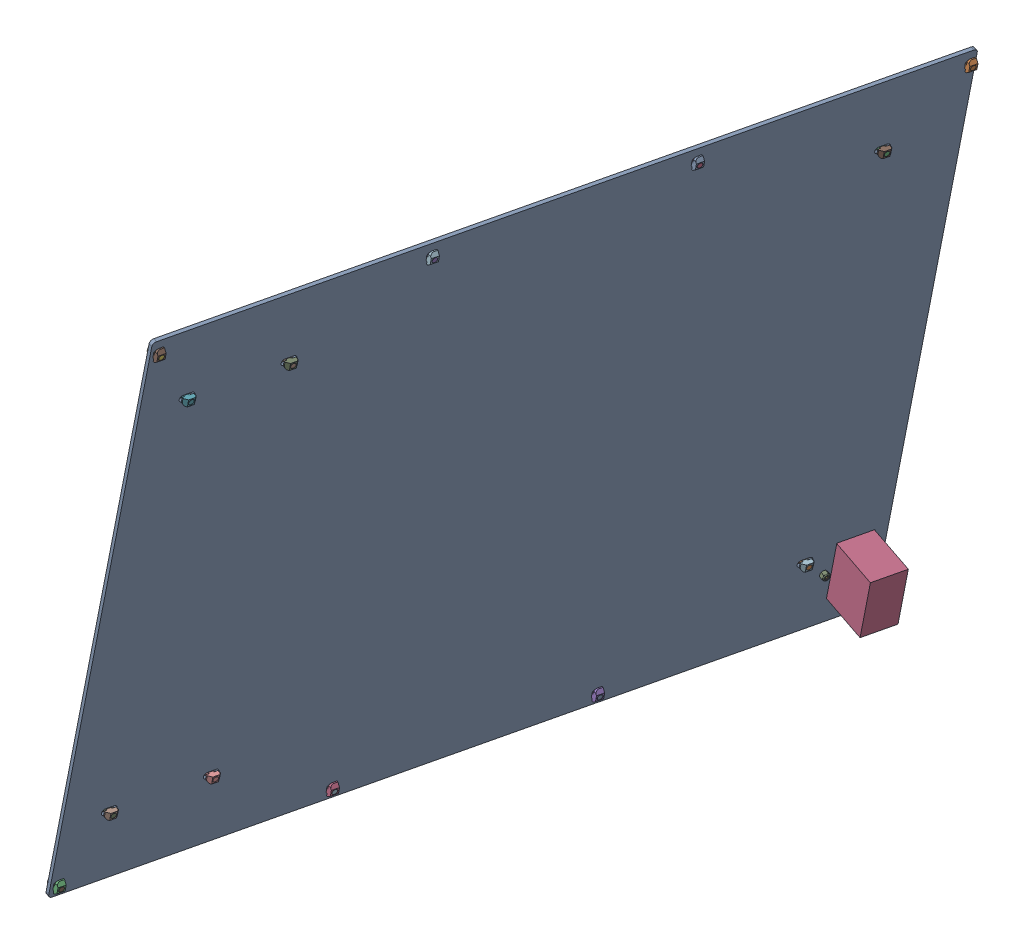
SolidWorks assembly left_side_panel_assembly, configuration Default. Lengths in mm.
Overall size (215.51 480.57 599.43).
34 component instances, 6 part files, 0 mates.
Components (placement in the parent):
- side_plates_120v side-1: side_plates_120v side [Default] at (-193.2218 26.2651 513.7471) x (0.192071 -0.031865 -0.980864) z (0.961323 -0.194929 0.194577) size (604 470 3)
- m5_low_profile_screw_template_M5 x 8-1: m5_low_profile_screw_template_M5 x 8 [Default] at (20.3229 456.5561 -69.1022) x (0.961323 -0.194929 0.194577) z (-0.194022 0.022125 0.980748) size (9.62 9 9)
- m5_low_profile_screw_template_M5 x 8-2: m5_low_profile_screw_template_M5 x 8 [Default] at (-0.1109 409.2938 -15.495) x (0.961323 -0.194929 0.194577) z (-0.197399 -0.9803 -0.006807) size (9.62 9 9)
- m5_low_profile_screw_template_M5 x 8-3: m5_low_profile_screw_template_M5 x 8 [Default] at (-18.0912 462.9292 127.0705) x (0.961323 -0.194929 0.194577) z (-0.194577 0.019338 0.980697) size (9.62 9 9)
- m5_low_profile_screw_template_M5 x 8-4: m5_low_profile_screw_template_M5 x 8 [Default] at (-55.3529 469.1111 317.3581) x (0.961323 -0.194929 0.194577) z (0.091886 0.892977 0.440623) size (9.62 9 9)
- m5_low_profile_screw_template_M5 x 8-5: m5_low_profile_screw_template_M5 x 8 [Default] at (-93.7671 475.4841 513.5308) x (0.961323 -0.194929 0.194577) z (-0.092861 0.435708 0.895285) size (9.62 9 9)
- m5_low_profile_screw_template_M5 x 8-6: m5_low_profile_screw_template_M5 x 8 [Default] at (-97.8749 425.5132 483.7645) x (0.961323 -0.194929 0.194577) z (-0.092861 0.435708 0.895285) size (9.62 9 9)
- m5_low_profile_screw_template_M5 x 8-7: m5_low_profile_screw_template_M5 x 8 [Default] at (-83.5416 423.1352 410.5676) x (0.961323 -0.194929 0.194577) z (-0.092861 0.435708 0.895285) size (9.62 9 9)
- m5_low_profile_screw_template_M5 x 8-8: m5_low_profile_screw_template_M5 x 8 [Default] at (-166.9647 82.4084 481.3819) x (0.961323 -0.194929 0.194577) z (0.091886 0.892977 0.440623) size (9.62 9 9)
- m5_low_profile_screw_template_M5 x 8-9: m5_low_profile_screw_template_M5 x 8 [Default] at (-152.6314 80.0304 408.185) x (0.961323 -0.194929 0.194577) z (0.091886 0.892977 0.440623) size (9.62 9 9)
- m5_low_profile_screw_template_M5 x 8-10: m5_low_profile_screw_template_M5 x 8 [Default] at (-182.5968 34.3493 510.4675) x (0.961323 -0.194929 0.194577) z (0.091886 0.892977 0.440623) size (9.62 9 9)
- m5_low_profile_screw_template_M5 x 8-11: m5_low_profile_screw_template_M5 x 8 [Default] at (-144.1827 27.9763 314.2947) x (0.961323 -0.194929 0.194577) z (0.091886 0.892977 0.440623) size (9.62 9 9)
- m5_low_profile_screw_template_M5 x 8-12: m5_low_profile_screw_template_M5 x 8 [Default] at (-106.921 21.7944 124.0072) x (0.961323 -0.194929 0.194577) z (0.091886 0.892977 0.440623) size (9.62 9 9)
- m5_low_profile_screw_template_M5 x 8-13: m5_low_profile_screw_template_M5 x 8 [Default] at (-69.2007 66.1889 -17.8776) x (0.961323 -0.194929 0.194577) z (0.091886 0.892977 0.440623) size (9.62 9 9)
- m5_low_profile_screw_template_M5 x 8-14: m5_low_profile_screw_template_M5 x 8 [Default] at (-68.5068 15.4214 -72.1655) x (0.961323 -0.194929 0.194577) z (0.091886 0.892977 0.440623) size (9.62 9 9)
- IEC320_C14_120V_socket-1: IEC320_C14_120V_socket [Default] at (-36.236 18.9955 -60.9923) x (-0.192071 0.031865 0.980864) z (-0.961323 0.194929 -0.194577) size (49 57.5 44.3)
- m3_10mm_flathead_screw_92125A130_92125A130-1: m3_10mm_flathead_screw_92125A130_92125A130 [Default] at (-73.0455 50.5315 -75.4693) x (-0.125947 0.317148 0.939976) z (-0.961323 0.194929 -0.194577) size (6 6 10.15)
- m3_10mm_flathead_screw_92125A130_92125A130-2: m3_10mm_flathead_screw_92125A130_92125A130 [Default] at (-80.7283 51.8061 -36.2347) x (-0.125947 0.317148 0.939976) z (-0.961323 0.194929 -0.194577) size (6 6 10.15)
- m3_locknut_93625A100-1: m3_locknut_93625A100 [Default] at (-66.4605 49.1962 -74.1364) x (-0.147902 -0.961323 -0.232342) z (-0.232342 -0.194577 0.952973) size (5.5 4 6.35)
- m3_locknut_93625A100-2: m3_locknut_93625A100 [Default] at (-74.1433 50.4708 -34.9019) x (-0.147902 -0.961323 -0.232342) z (-0.232342 -0.194577 0.952973) size (5.5 4 6.35)
- m5_locking_t_nut_20x20_generic-1: m5_locking_t_nut_20x20_generic [Default] at (-93.1909 475.3885 510.5882) x (0.197399 0.9803 0.006807) z (-0.192071 0.031865 0.980864) size (10 4.5 6)
- m5_locking_t_nut_20x20_generic-2: m5_locking_t_nut_20x20_generic [Default] at (-54.7767 469.0155 314.4155) x (0.197399 0.9803 0.006807) z (-0.192071 0.031865 0.980864) size (10 4.5 6)
- m5_locking_t_nut_20x20_generic-3: m5_locking_t_nut_20x20_generic [Default] at (-17.515 462.8336 124.128) x (0.197399 0.9803 0.006807) z (-0.192071 0.031865 0.980864) size (10 4.5 6)
- m5_locking_t_nut_20x20_generic-4: m5_locking_t_nut_20x20_generic [Default] at (20.8992 456.4605 -72.0448) x (0.197399 0.9803 0.006807) z (-0.192071 0.031865 0.980864) size (10 4.5 6)
- m5_locking_t_nut_20x20_generic-5: m5_locking_t_nut_20x20_generic [Default] at (-182.0206 34.2537 507.5249) x (0.197399 0.9803 0.006807) z (-0.192071 0.031865 0.980864) size (10 4.5 6)
- m5_locking_t_nut_20x20_generic-6: m5_locking_t_nut_20x20_generic [Default] at (-143.6065 27.8807 311.3522) x (0.197399 0.9803 0.006807) z (-0.192071 0.031865 0.980864) size (10 4.5 6)
- m5_locking_t_nut_20x20_generic-7: m5_locking_t_nut_20x20_generic [Default] at (-106.3447 21.6988 121.0646) x (0.197399 0.9803 0.006807) z (-0.192071 0.031865 0.980864) size (10 4.5 6)
- m5_locking_t_nut_20x20_generic-8: m5_locking_t_nut_20x20_generic [Default] at (-67.9306 15.3258 -75.1081) x (0.197399 0.9803 0.006807) z (-0.192071 0.031865 0.980864) size (10 4.5 6)
- m5_locking_t_nut_20x20_generic-9: m5_locking_t_nut_20x20_generic [Default] at (-98.4671 422.5723 483.7441) x (0.192071 -0.031865 -0.980864) z (0.197399 0.9803 0.006807) size (10 4.5 6)
- m5_locking_t_nut_20x20_generic-10: m5_locking_t_nut_20x20_generic [Default] at (-167.5569 79.4675 481.3615) x (0.192071 -0.031865 -0.980864) z (0.197399 0.9803 0.006807) size (10 4.5 6)
- m5_locking_t_nut_20x20_generic-11: m5_locking_t_nut_20x20_generic [Default] at (-84.1338 420.1943 410.5472) x (0.192071 -0.031865 -0.980864) z (0.197399 0.9803 0.006807) size (10 4.5 6)
- m5_locking_t_nut_20x20_generic-12: m5_locking_t_nut_20x20_generic [Default] at (-153.2236 77.0895 408.1646) x (0.192071 -0.031865 -0.980864) z (0.197399 0.9803 0.006807) size (10 4.5 6)
- m5_locking_t_nut_20x20_generic-13: m5_locking_t_nut_20x20_generic [Default] at (-0.7031 406.3529 -15.5155) x (0.192071 -0.031865 -0.980864) z (0.197399 0.9803 0.006807) size (10 4.5 6)
- m5_locking_t_nut_20x20_generic-14: m5_locking_t_nut_20x20_generic [Default] at (-69.7929 63.248 -17.8981) x (0.192071 -0.031865 -0.980864) z (0.197399 0.9803 0.006807) size (10 4.5 6)
